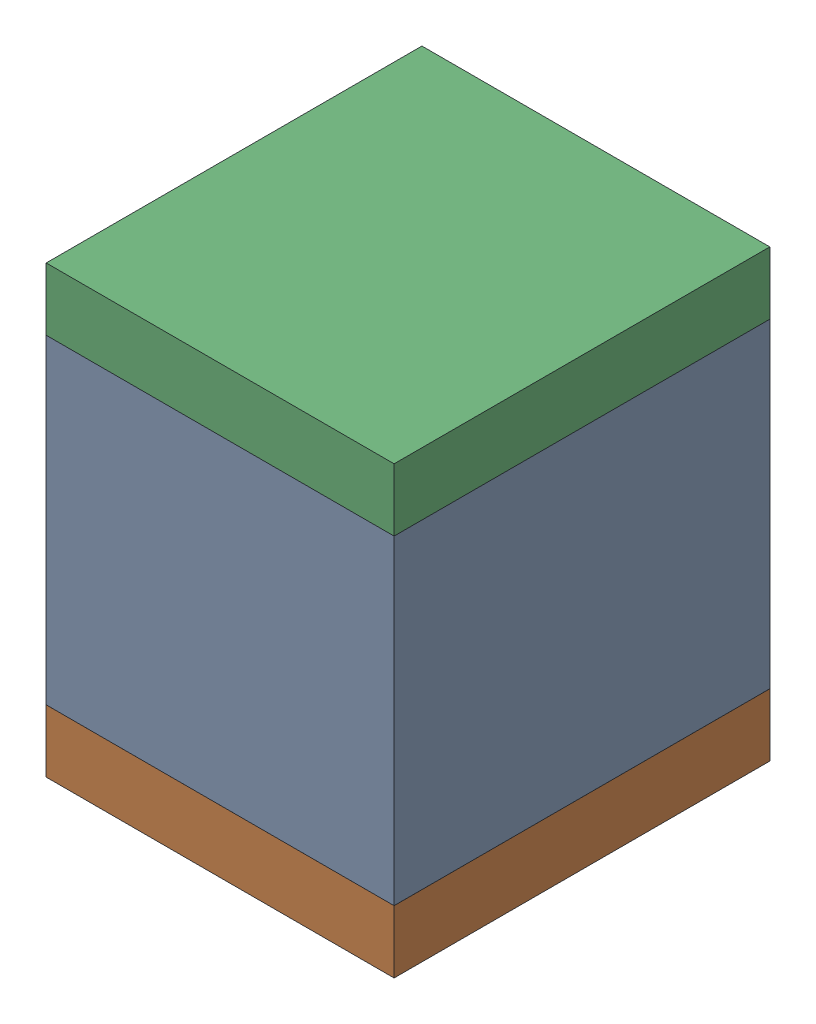
SolidWorks assembly C9, configuration ﾃﾞﾌｫﾙﾄ. Lengths in mm.
Overall size (2.5 3.2 2.7).
6 component instances, 2 part files, 0 mates.
Components (placement in the parent):
- 689260016-1: 689260016 [ﾃﾞﾌｫﾙﾄ] at (46.75 58.5 0) size (2.5 2.3 2.7)
  - Extruded_6-1: Extruded_6 [ﾃﾞﾌｫﾙﾄ] at origin size (2.5 2.3 2.7)
- 689260152-1: 689260152 [ﾃﾞﾌｫﾙﾄ] at (46.7501 57.125 0) size (2.5 0.45 2.7)
  - Extruded_7-1: Extruded_7 [ﾃﾞﾌｫﾙﾄ] at origin size (2.5 0.45 2.7)
- 689260152-2: 689260152 [ﾃﾞﾌｫﾙﾄ] at (46.7501 59.875 0) size (2.5 0.45 2.7)
  - Extruded_7-1: Extruded_7 [ﾃﾞﾌｫﾙﾄ] at origin size (2.5 0.45 2.7)
